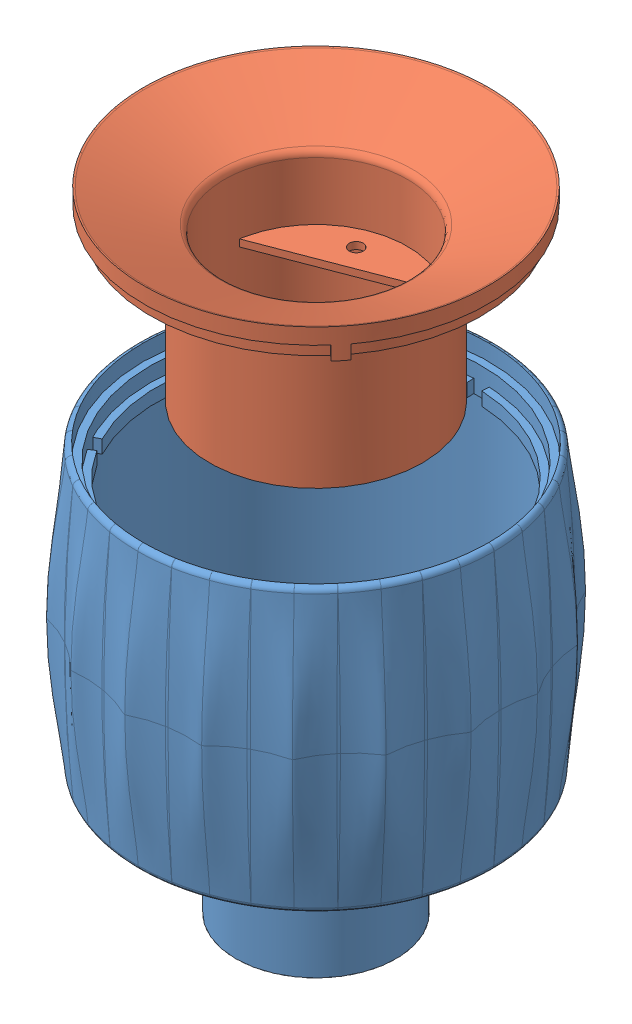
SolidWorks assembly Housing Assembly, configuration Default. Lengths in mm.
Overall size (63.85 90.48 63.85).
2 component instances, 2 part files, 1 mates.
Components (placement in the parent):
- Pinch_091812-Outer-1: Pinch_091812-Outer [Default] at origin size (54.06 58.49 54.87)
- Pinch_091812-Inner-1: Pinch_091812-Inner [Default] at (0 31.8323 0) x (0.356989 0 0.934108) z (-0.934108 0 0.356989) size (49.46 27.01 49.45)
Mates (geometry in assembly coordinates):
- Concentric4: concentric aligned: cylinder of Pinch_091812-Outer-1 through (0 -15.5499 0) axis (0 1 0) radius 24.7774; cylinder of Pinch_091812-Inner-1 through (0 18.5737 0) axis (0 1 0) radius 13.1282
